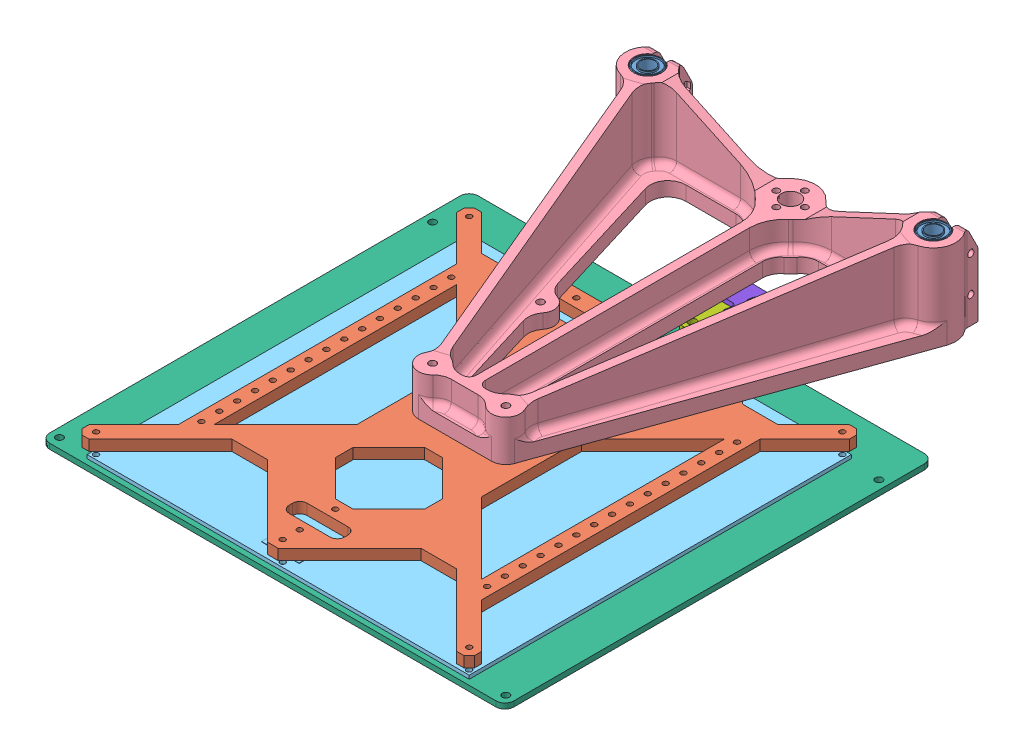
SolidWorks assembly Bed, configuration Predeterminado. Lengths in mm.
Overall size (260 98.36 306).
16 component instances, 12 part files, 39 mates.
Components (placement in the parent):
- Z_axis_carriage_v2-1: Z_axis_carriage_v2 [Predeterminado] at (-1.4714 -19.6675 118) size (185 48 204) (hidden)
- LM8UU-1: LM8UU [Default] at (78.5286 -7.6675 118) x (0 -1 0) z (-1 0 0) size (24 15 15)
- LM8UU-2: LM8UU [Default] at (78.5286 16.3325 118) x (0 -1 0) z (-1 0 0) size (24 15 15)
- LM8UU-3: LM8UU [Default] at (-81.4714 -7.6675 118) x (0 -1 0) z (1 0 0) size (24 15 15)
- LM8UU-4: LM8UU [Default] at (-81.4714 16.3325 118) x (0 -1 0) z (1 0 0) size (24 15 15)
- bed_frame-1: bed_frame [Predeterminado] at (-1.4714 -19.6675 298) x (0 0 1) z (0 -1 0) size (220 220 6)
- z_switch_support-1: z_switch_support [Predeterminado] at (51.0286 -5.6675 108) x (1 0 0) z (0 1 0) size (30 6 60) (hidden)
- Endstop-1: Endstop [Predeterminado] at (61.0286 -55.4675 111.2) x (-1 0 0) z (0 0 1) size (21.95 27.11 6.4) (hidden)
- z_lead_screw_nut-1: z_lead_screw_nut [Predeterminado] at (-1.4714 -24.6675 118) size (22 15.79 22)
- z_lead_screw_nut-2: z_lead_screw_nut [Predeterminado] at (-1.4714 13.3325 118) x (0.837169 0 0.546944) z (0.546944 0 -0.837169) size (22 15.79 22) (hidden)
- Z_axis_carriage_lead_screw-1: Z_axis_carriage_lead_screw [Predeterminado] at (-1.4714 -19.6675 118) size (185.85 48 204)
- bed_MK2-1: bed_MK2 [Predeterminado] at (-1.4463 -32.6675 298.0251) size (214 2.2 214)
- Alu_bed-1: Alu_bed [Predeterminado] at (-1.4714 -35.6675 298) x (-1 0 0) z (0 0 -1) size (260 3 240)
- camera_arm_3-1: camera_arm_3 [Predeterminado] at (-1.5421 -28.6675 177.9995) x (0.014141 0 -0.9999) z (-0.9999 0 -0.014141) size (23 7 10)
- camera_arm_v-1: camera_arm_v [Predeterminado] at (-1.3136 -26.2636 161.8381) x (-0.9999 0 -0.014141) z (-0.001795 -0.991909 0.126935) size (20 29.66 10.16)
- camera housing-1: camera housing [Predeterminado] at (-0.9037 -32.03 132.8583) x (-0.9999 0 -0.014141) z (-0.01414 0.004557 0.99989) size (30 38 8)
Mates (geometry in assembly coordinates):
- Concéntrica1: concentric anti-aligned: cylinder of Z_axis_carriage_v2-1 through (78.5286 28.3325 118) axis (0 -1 0) radius 7.75; cylinder of LM8UU-1 through (78.5286 38.022 118) axis (0 1 0) radius 7.5
- Coincidente1: coincident aligned: plane of Z_axis_carriage_v2-1 through (-81.4714 -19.6675 118) normal (0 -1 0); plane of LM8UU-1 through (78.5286 -19.6675 118) normal (0 -1 0)
- Paralelo1: parallel anti-aligned: plane of Z_axis_carriage_v2-1 through (74.5286 28.3325 102) normal (1 0 0); plane of LM8UU-1 through (78.5286 -7.6675 118) normal (-1 0 0)
- Concéntrica2: concentric anti-aligned: cylinder of Z_axis_carriage_v2-1 through (78.5286 28.3325 118) axis (0 -1 0) radius 7.75; cylinder of LM8UU-2 through (78.5286 62.022 118) axis (0 1 0) radius 7.5
- Coincidente3: coincident aligned: plane of Z_axis_carriage_v2-1 through (78.5286 28.3325 118) normal (0 1 0); plane of LM8UU-2 through (78.5286 28.3325 118) normal (0 1 0)
- Paralelo2: parallel anti-aligned: plane of Z_axis_carriage_v2-1 through (74.5286 28.3325 102) normal (1 0 0); plane of LM8UU-2 through (78.5286 16.3325 118) normal (-1 0 0)
- Concéntrica3: concentric anti-aligned: cylinder of Z_axis_carriage_v2-1 through (-81.4714 28.3325 118) axis (0 -1 0) radius 7.75; cylinder of LM8UU-3 through (-81.4714 38.022 118) axis (0 1 0) radius 7.5
- Coincidente5: coincident aligned: plane of Z_axis_carriage_v2-1 through (-81.4714 -19.6675 118) normal (0 -1 0); plane of LM8UU-3 through (-81.4714 -19.6675 118) normal (0 -1 0)
- Paralelo3: parallel anti-aligned: plane of Z_axis_carriage_v2-1 through (-77.4714 28.3325 102) normal (-1 0 0); plane of LM8UU-3 through (-81.4714 -7.6675 118) normal (1 0 0)
- Concéntrica4: concentric anti-aligned: cylinder of Z_axis_carriage_v2-1 through (-81.4714 28.3325 118) axis (0 -1 0) radius 7.75; cylinder of LM8UU-4 through (-81.4714 62.022 118) axis (0 1 0) radius 7.5
- Coincidente7: coincident aligned: plane of Z_axis_carriage_v2-1 through (-81.4714 28.3325 118) normal (0 1 0); plane of LM8UU-4 through (-81.4714 28.3325 118) normal (0 1 0)
- Paralelo4: parallel anti-aligned: plane of Z_axis_carriage_v2-1 through (-77.4714 28.3325 102) normal (-1 0 0); plane of LM8UU-4 through (-81.4714 16.3325 118) normal (1 0 0)
- Coincidente9: coincident anti-aligned: plane of Z_axis_carriage_v2-1 through (-81.4714 -19.6675 118) normal (0 -1 0); plane of bed_frame-1 through (-1.4714 -19.6675 298) normal (0 1 0)
- Concéntrica5: concentric anti-aligned: cylinder of Z_axis_carriage_v2-1 through (19.0286 -11.6675 298) axis (0 -1 0) radius 2; cylinder of bed_frame-1 through (19.0286 -25.6675 298) axis (0 1 0) radius 1.5
- Concéntrica6: concentric anti-aligned: cylinder of Z_axis_carriage_v2-1 through (-21.9714 -11.6675 298) axis (0 -1 0) radius 2; cylinder of bed_frame-1 through (-21.9714 -25.6675 298) axis (0 1 0) radius 1.5
- Concéntrica7: concentric anti-aligned: cylinder of Z_axis_carriage_v2-1 through (43.5286 -15.6675 118) axis (0 0 -1) radius 2.5; cylinder of z_switch_support-1 through (43.5286 -15.6675 102) axis (0 0 1) radius 2
- Coincidente10: coincident anti-aligned: plane of Z_axis_carriage_v2-1 through (-81.4714 -11.6675 108) normal (0 0 -1); plane of z_switch_support-1 through (51.0286 -5.6675 108) normal (0 0 1)
- Concéntrica8: concentric anti-aligned: cylinder of Z_axis_carriage_v2-1 through (58.5286 -15.6675 118) axis (0 0 -1) radius 2.5; cylinder of z_switch_support-1 through (58.5286 -15.6675 102) axis (0 0 1) radius 2
- Coincidente11: coincident anti-aligned: plane of z_switch_support-1 through (51.0286 -5.6675 108) normal (0 0 1); plane of Endstop-1 through (61.0286 -55.4675 108) normal (0 0 -1)
- Concéntrica9: concentric anti-aligned: cylinder of z_switch_support-1 through (55.7786 -58.3675 102) axis (0 0 1) radius 1.35; cylinder of Endstop-1 through (55.7786 -58.3675 114.4) axis (0 0 -1) radius 1.25
- Concéntrica10: concentric anti-aligned: cylinder of z_switch_support-1 through (46.2786 -58.3675 102) axis (0 0 1) radius 1.35; cylinder of Endstop-1 through (46.2786 -58.3675 114.4) axis (0 0 -1) radius 1.25
- Coincidente12: coincident anti-aligned: axis of Z_axis_carriage_v2-1 through (-1.4714 -11.6675 118) axis (0 -1 0); axis of z_lead_screw_nut-1 through (-1.4714 -24.6675 118) axis (0 1 0)
- Coincidente13: coincident anti-aligned: plane of Z_axis_carriage_v2-1 through (-81.4714 -19.6675 118) normal (0 -1 0); plane of z_lead_screw_nut-1 through (9.5286 -19.6675 118) normal (0 1 0)
- Coincidente14: coincident anti-aligned: plane of Z_axis_carriage_v2-1 through (-1.4714 8.3325 118) normal (0 1 0); plane of z_lead_screw_nut-2 through (7.7374 8.3325 124.0164) normal (0 -1 0)
- Concéntrica12: concentric aligned: cylinder of Z_axis_carriage_v2-1 through (-1.4714 -19.6675 118) axis (0 1 0) radius 5.25; cylinder of z_lead_screw_nut-2 through (-1.4714 26.0623 118) axis (0 1 0) radius 5.1
- Coincidente15: coordinate: point of Z_axis_carriage_v2-1; point of Z_axis_carriage_lead_screw-1
- Distancia1: distance = 5 mm anti-aligned: plane of bed_MK2-1 through (-1.4463 -30.6675 298.0251) normal (0 1 0); plane of bed_frame-1 through (-1.4714 -25.6675 298) normal (0 -1 0)
- Concéntrica13: concentric aligned: cylinder of bed_frame-1 through (103.0286 -25.6675 402.5) axis (0 1 0) radius 1.5; cylinder of bed_MK2-1 through (103.0286 -30.6675 402.5) axis (0 1 0) radius 1.5
- Paralelo5: parallel aligned: cylinder of bed_frame-1 through (-105.9714 -25.6675 193.5) axis (0 1 0) radius 1.5; cylinder of bed_MK2-1 through (-105.9211 -30.6675 193.5503) axis (0 1 0) radius 1.5
- Coincidente17: coincident anti-aligned: plane of bed_MK2-1 through (-1.4463 -32.6675 298.0251) normal (0 -1 0); plane of Alu_bed-1 through (-1.4714 -32.6675 298) normal (0 1 0)
- Concéntrica14: concentric anti-aligned: cylinder of bed_MK2-1 through (103.0286 -30.6675 402.5) axis (0 1 0) radius 1.5; cylinder of Alu_bed-1 through (103.0286 -32.6675 402.5) axis (0 -1 0) radius 1.5
- Paralelo7: parallel aligned: plane of Alu_bed-1 through (128.5286 -32.6675 168) normal (0 0 -1); plane of bed_MK2-1 through (105.5537 -32.6675 191.0251) normal (0 0 -1)
- Coincidente23: coincident aligned: axis of camera_arm_v-1 through (-9.1597 -36.0117 136.7601) axis (0.9999 0 0.014141); axis of camera housing-1 through (7.5386 -36.0117 136.9963) axis (0.9999 0 0.014141)
- Distancia4: distance = 0.3 mm anti-aligned: plane of camera_arm_v-1 through (7.1482 -38.7217 143.3872) normal (0.9999 0 0.014141); plane of camera housing-1 through (7.4823 -31.9935 140.9776) normal (-0.9999 0 -0.014141)
- Coincidente28: coincident anti-aligned: axis of camera_arm_3-1 through (3.7261 -31.6675 159.0721) axis (-0.9999 0 -0.014141); axis of camera_arm_v-1 through (3.926 -31.6675 159.0749) axis (0.9999 0 0.014141)
- Coincidente32: coincident aligned: axis of Alu_bed-1 through (-1.4714 -32.6675 173) axis (0 -1 0); axis of camera_arm_3-1 through (-1.4714 -28.6675 173) axis (0 -1 0)
- Coincidente33: coincident anti-aligned: plane of Alu_bed-1 through (-1.4714 -32.6675 298) normal (0 1 0); plane of camera_arm_3-1 through (-1.5421 -32.6675 177.9995) normal (0 -1 0)
- Distancia9: distance = 0.2 mm anti-aligned: plane of camera_arm_v-1 through (3.868 -36.1827 163.1809) normal (-0.9999 0 -0.014141); plane of camera_arm_3-1 through (3.4574 -35.6675 178.0702) normal (0.9999 0 0.014141)
- Concéntrica17: concentric anti-aligned: cylinder of bed_frame-1 through (-105.9714 -25.6675 193.5) axis (0 1 0) radius 1.5; cylinder of Alu_bed-1 through (-105.9714 -32.6675 193.5) axis (0 -1 0) radius 1.5
